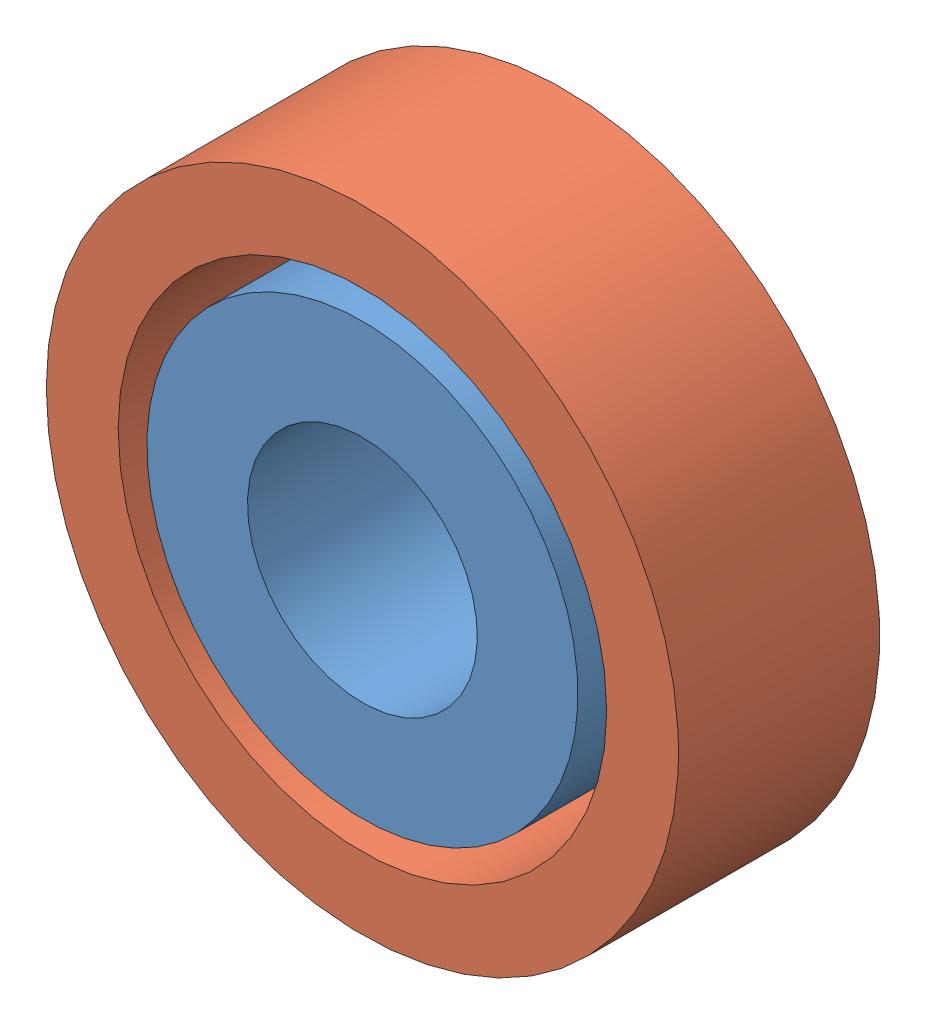
SolidWorks assembly 608 bearing, configuration Default. Lengths in mm.
Overall size (22 22 7).
2 component instances, 2 part files, 2 mates.
Components (placement in the parent):
- inner race-1: inner race [Default] at (-10.3949 5.6455 9.7773) x (0.283515 0.958968 0) z (0 0 1) size (15 15 7)
- outer race-1: outer race [Default] at (-10.3949 5.6455 9.7773) size (22 22 7)
Mates (geometry in assembly coordinates):
- Concentric1: concentric aligned: cylinder of inner race-1 through (-10.3949 5.6455 16.7773) axis (0 0 -1) radius 7.5; cylinder of outer race-1 through (-10.3949 5.6455 16.7773) axis (0 0 -1) radius 8.5
- Coincident1: coincident aligned: plane of inner race-1 through (-10.3949 5.6455 9.7773) normal (0 0 -1); plane of outer race-1 through (-10.3949 5.6455 9.7773) normal (0 0 -1)
